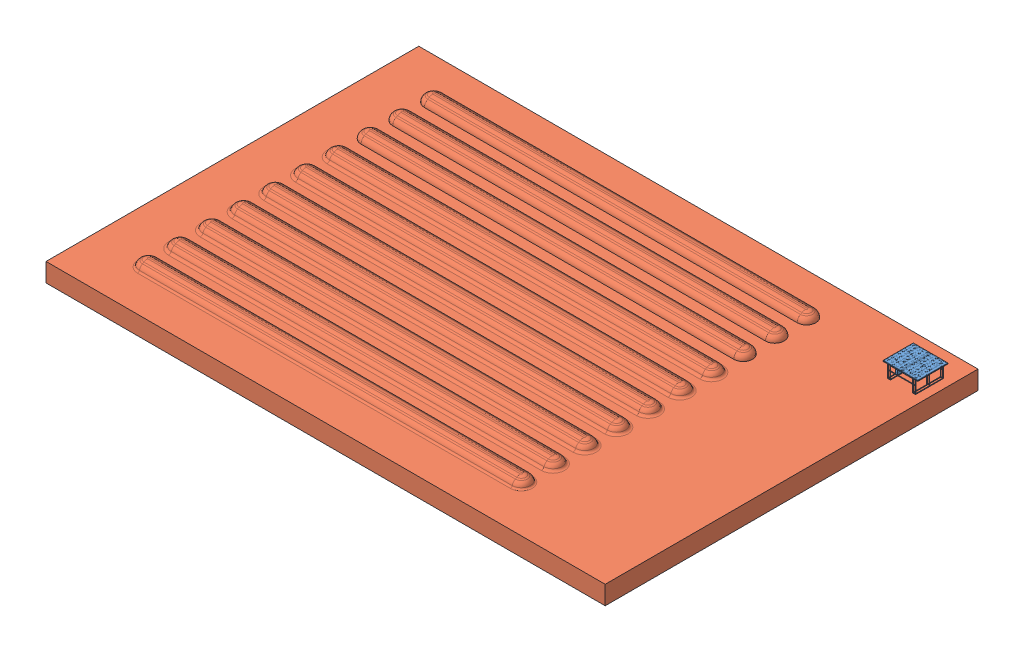
SolidWorks assembly Assem1, configuration Default. Lengths in mm.
Overall size (30000 2082.8 20000).
2 component instances, 2 part files, 3 mates.
Components (placement in the parent):
- Main Body-1: Main Body [Default] at (14067 305.6161 -7580.9433) size (1866 777.18 1624.9)
- kebun-1: kebun [Default] at origin size (30000 1400 20000)
Mates (geometry in assembly coordinates):
- Coincident5: coordinate: point of kebun-1
- Coincident6: coincident aligned: plane of Main Body-1 through (15000 4087.3009 13440.3961) normal (1 0 0); plane of kebun-1 through (15000 -1000 -10000) normal (1 0 0)
- Parallel2: parallel aligned: plane of Main Body-1 through (14067 3330.1161 12627.9437) normal (0 1 0); plane of kebun-1 through (0 0 0) normal (0 1 0)
